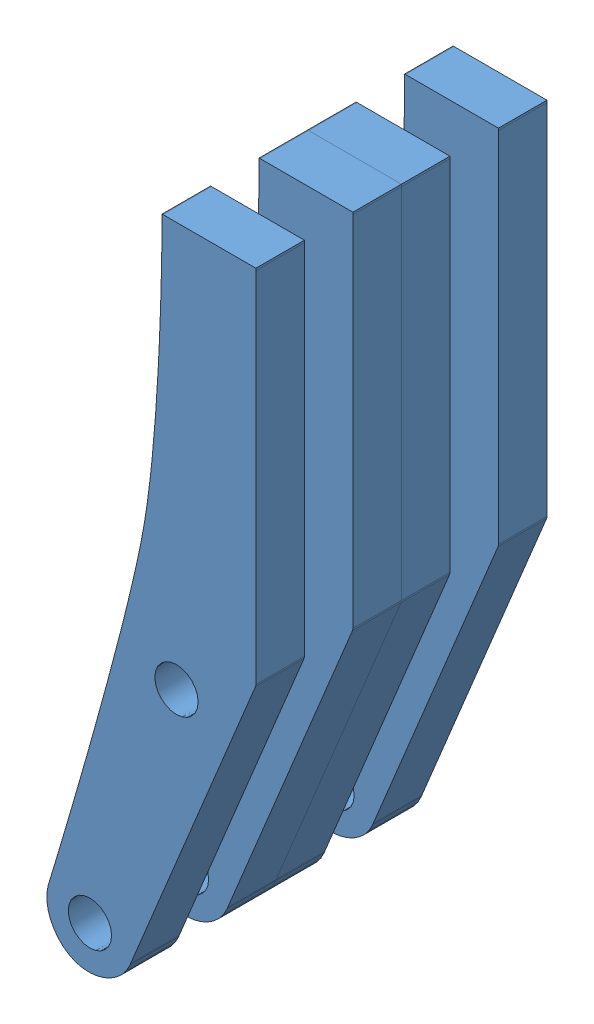
SolidWorks assembly upper_fingers, configuration Default. Lengths in mm.
Overall size (15.08 50 21).
4 component instances, 1 part files, 0 mates.
Components (placement in the parent):
- gripper2-1: gripper2 [Default] at origin size (15.08 50 3.5)
- gripper2-2: gripper2 [Default] at (0 0 -7) size (15.08 50 3.5)
- gripper2-3: gripper2 [Default] at (0 0 -10.5) size (15.08 50 3.5)
- gripper2-4: gripper2 [Default] at (0 0 -17.5) size (15.08 50 3.5)
